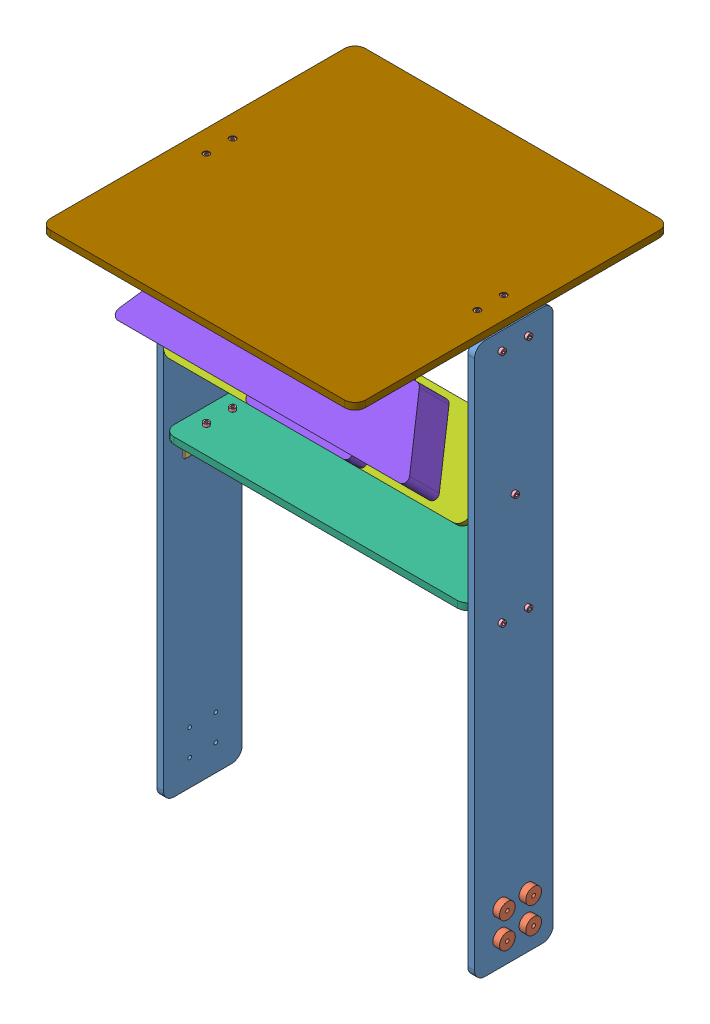
SolidWorks assembly Assembly_real_stairs_top_2, configuration Default. Lengths in mm.
Overall size (315.39 531.34 300).
62 component instances, 9 part files, 50 mates.
Components (placement in the parent):
- Part11-4: Part11 [Default] at (362.0256 34.666 386.9752) x (0 -1 0) z (0 0 1) size (525 6.35 75)
- Part11-5: Part11 [Default] at (72.0356 34.666 386.9752) x (0 -1 0) z (0 0 -1) size (525 6.35 75)
- washer-17: washer [Default] at (368.3756 -202.834 399.4752) x (0 0 -1) z (0 -1 0) size (15 6.35 15)
- washer-18: washer [Default] at (368.3756 -177.834 399.4752) x (0 0 -1) z (0 -1 0) size (15 6.35 15)
- washer-19: washer [Default] at (368.3756 -202.834 374.4752) x (0 0 -1) z (0 -1 0) size (15 6.35 15)
- washer-20: washer [Default] at (368.3756 -177.834 374.4752) x (0 0 -1) z (0 -1 0) size (15 6.35 15)
- washer-21: washer [Default] at (65.6856 -202.834 399.4752) x (0 0 1) z (0 -1 0) size (15 6.35 15)
- washer-22: washer [Default] at (65.6856 -177.834 399.4752) x (0 0 1) z (0 -1 0) size (15 6.35 15)
- washer-23: washer [Default] at (65.6856 -202.834 374.4752) x (0 0 1) z (0 -1 0) size (15 6.35 15)
- washer-24: washer [Default] at (65.6856 -177.834 374.4752) x (0 0 1) z (0 -1 0) size (15 6.35 15)
- 1556A410_BRACKET-17: 1556A410_BRACKET [1556A41] at (72.0356 73.041 399.4752) x (1 0 0) z (0 -1 0) size (25.4 12.7 25.4)
- 91290A123_BLACK-OXIDE CLASS 12.9 SOCKET HEAD CAP SCREW-23: 91290A123_BLACK-OXIDE CLASS 12.9 SOCKET HEAD CAP SCREW [91290A123] at (85.6856 57.166 399.4752) x (0 0 -1) z (1 0 0) size (5.5 5.5 23.27)
- 92497A200_ZINC YELLOW-CHROMATE PLATED STEEL HEX NUT-24: 92497A200_ZINC YELLOW-CHROMATE PLATED STEEL HEX NUT [92497A200] at (75.0136 57.166 399.4752) x (0 0 -1) z (1 0 0) size (5.5 6.35 2.78)
- 1556A410_BRACKET-18: 1556A410_BRACKET [1556A41] at (72.0356 73.041 374.4752) x (1 0 0) z (0 -1 0) size (25.4 12.7 25.4)
- 91290A123_BLACK-OXIDE CLASS 12.9 SOCKET HEAD CAP SCREW-24: 91290A123_BLACK-OXIDE CLASS 12.9 SOCKET HEAD CAP SCREW [91290A123] at (85.6856 57.166 374.4752) x (0 0 -1) z (1 0 0) size (5.5 5.5 23.27)
- 92497A200_ZINC YELLOW-CHROMATE PLATED STEEL HEX NUT-25: 92497A200_ZINC YELLOW-CHROMATE PLATED STEEL HEX NUT [92497A200] at (75.0136 57.166 374.4752) x (0 0 -1) z (1 0 0) size (5.5 6.35 2.78)
- 1556A410_BRACKET-19: 1556A410_BRACKET [1556A41] at (72.0356 297.161 399.4752) x (1 0 0) z (0 -1 0) size (25.4 12.7 25.4)
- 91290A123_BLACK-OXIDE CLASS 12.9 SOCKET HEAD CAP SCREW-25: 91290A123_BLACK-OXIDE CLASS 12.9 SOCKET HEAD CAP SCREW [91290A123] at (85.6856 281.286 399.4752) x (0 0 -1) z (1 0 0) size (5.5 5.5 23.27)
- 92497A200_ZINC YELLOW-CHROMATE PLATED STEEL HEX NUT-26: 92497A200_ZINC YELLOW-CHROMATE PLATED STEEL HEX NUT [92497A200] at (75.0136 281.286 399.4752) x (0 0 -1) z (1 0 0) size (5.5 6.35 2.78)
- 1556A410_BRACKET-20: 1556A410_BRACKET [1556A41] at (72.0356 297.161 374.4752) x (1 0 0) z (0 -1 0) size (25.4 12.7 25.4)
- 91290A123_BLACK-OXIDE CLASS 12.9 SOCKET HEAD CAP SCREW-26: 91290A123_BLACK-OXIDE CLASS 12.9 SOCKET HEAD CAP SCREW [91290A123] at (85.6856 281.286 374.4752) x (0 0 -1) z (1 0 0) size (5.5 5.5 23.27)
- 92497A200_ZINC YELLOW-CHROMATE PLATED STEEL HEX NUT-27: 92497A200_ZINC YELLOW-CHROMATE PLATED STEEL HEX NUT [92497A200] at (75.0136 281.286 374.4752) x (0 0 -1) z (1 0 0) size (5.5 6.35 2.78)
- 1556A410_BRACKET-21: 1556A410_BRACKET [1556A41] at (362.0256 73.041 399.4752) x (-1 0 0) z (0 -1 0) size (25.4 12.7 25.4)
- 91290A123_BLACK-OXIDE CLASS 12.9 SOCKET HEAD CAP SCREW-27: 91290A123_BLACK-OXIDE CLASS 12.9 SOCKET HEAD CAP SCREW [91290A123] at (348.3756 57.166 399.4752) x (0 0 1) z (-1 0 0) size (5.5 5.5 23.27)
- 92497A200_ZINC YELLOW-CHROMATE PLATED STEEL HEX NUT-28: 92497A200_ZINC YELLOW-CHROMATE PLATED STEEL HEX NUT [92497A200] at (359.0476 57.166 399.4752) x (0 0 -1) z (1 0 0) size (5.5 6.35 2.78)
- 1556A410_BRACKET-22: 1556A410_BRACKET [1556A41] at (362.0256 73.041 374.4752) x (-1 0 0) z (0 -1 0) size (25.4 12.7 25.4)
- 1556A410_BRACKET-23: 1556A410_BRACKET [1556A41] at (362.0256 297.161 399.4752) x (-1 0 0) z (0 -1 0) size (25.4 12.7 25.4)
- 1556A410_BRACKET-24: 1556A410_BRACKET [1556A41] at (362.0256 297.161 374.4752) x (-1 0 0) z (0 -1 0) size (25.4 12.7 25.4)
- 91290A123_BLACK-OXIDE CLASS 12.9 SOCKET HEAD CAP SCREW-28: 91290A123_BLACK-OXIDE CLASS 12.9 SOCKET HEAD CAP SCREW [91290A123] at (348.3756 57.166 374.4752) x (0 0 1) z (-1 0 0) size (5.5 5.5 23.27)
- 91290A123_BLACK-OXIDE CLASS 12.9 SOCKET HEAD CAP SCREW-29: 91290A123_BLACK-OXIDE CLASS 12.9 SOCKET HEAD CAP SCREW [91290A123] at (348.3756 281.286 399.4752) x (0 0 1) z (-1 0 0) size (5.5 5.5 23.27)
- 91290A123_BLACK-OXIDE CLASS 12.9 SOCKET HEAD CAP SCREW-30: 91290A123_BLACK-OXIDE CLASS 12.9 SOCKET HEAD CAP SCREW [91290A123] at (348.3756 281.286 374.4752) x (0 0 1) z (-1 0 0) size (5.5 5.5 23.27)
- 92497A200_ZINC YELLOW-CHROMATE PLATED STEEL HEX NUT-29: 92497A200_ZINC YELLOW-CHROMATE PLATED STEEL HEX NUT [92497A200] at (359.0476 57.166 374.4752) x (0 0 -1) z (1 0 0) size (5.5 6.35 2.78)
- 92497A200_ZINC YELLOW-CHROMATE PLATED STEEL HEX NUT-30: 92497A200_ZINC YELLOW-CHROMATE PLATED STEEL HEX NUT [92497A200] at (359.0476 281.286 399.4752) x (0 0 -1) z (1 0 0) size (5.5 6.35 2.78)
- 92497A200_ZINC YELLOW-CHROMATE PLATED STEEL HEX NUT-31: 92497A200_ZINC YELLOW-CHROMATE PLATED STEEL HEX NUT [92497A200] at (359.0476 281.286 374.4752) x (0 0 -1) z (1 0 0) size (5.5 6.35 2.78)
- Part5-2: Part5 [Default] at (217.0306 73.041 386.9752) size (290 6.35 75)
- 91290A123_BLACK-OXIDE CLASS 12.9 SOCKET HEAD CAP SCREW-31: 91290A123_BLACK-OXIDE CLASS 12.9 SOCKET HEAD CAP SCREW [91290A123] at (87.9106 59.391 399.4752) x (1 0 0) z (0 -1 0) size (5.5 5.5 23.27)
- 92497A200_ZINC YELLOW-CHROMATE PLATED STEEL HEX NUT-33: 92497A200_ZINC YELLOW-CHROMATE PLATED STEEL HEX NUT [92497A200] at (87.9106 70.063 399.4752) x (1 0 0) z (0 -1 0) size (5.5 6.35 2.78)
- 91290A123_BLACK-OXIDE CLASS 12.9 SOCKET HEAD CAP SCREW-32: 91290A123_BLACK-OXIDE CLASS 12.9 SOCKET HEAD CAP SCREW [91290A123] at (87.9106 59.391 374.4752) x (1 0 0) z (0 -1 0) size (5.5 5.5 23.27)
- 92497A200_ZINC YELLOW-CHROMATE PLATED STEEL HEX NUT-34: 92497A200_ZINC YELLOW-CHROMATE PLATED STEEL HEX NUT [92497A200] at (87.9106 70.063 374.4752) x (1 0 0) z (0 -1 0) size (5.5 6.35 2.78)
- 91290A123_BLACK-OXIDE CLASS 12.9 SOCKET HEAD CAP SCREW-38: 91290A123_BLACK-OXIDE CLASS 12.9 SOCKET HEAD CAP SCREW [91290A123] at (346.1506 59.391 399.4752) x (1 0 0) z (0 -1 0) size (5.5 5.5 23.27)
- 92497A200_ZINC YELLOW-CHROMATE PLATED STEEL HEX NUT-40: 92497A200_ZINC YELLOW-CHROMATE PLATED STEEL HEX NUT [92497A200] at (346.1506 70.063 399.4752) x (1 0 0) z (0 -1 0) size (5.5 6.35 2.78)
- 1556A410_BRACKET-25: 1556A410_BRACKET [1556A41] at (72.0356 168.3913 398.2005) x (1 0 0) z (0 -0.707107 -0.707107) size (25.4 12.7 25.4)
- 1556A410_BRACKET-26: 1556A410_BRACKET [1556A41] at (362.0256 168.3913 398.2005) x (-1 0 0) z (0 -0.707107 -0.707107) size (25.4 12.7 25.4)
- Part2-2: Part2 [Default] at (217.0306 168.3913 398.2005) x (1 0 0) z (0 -0.707107 0.707107) size (290 6.35 75)
- 91290A123_BLACK-OXIDE CLASS 12.9 SOCKET HEAD CAP SCREW-43: 91290A123_BLACK-OXIDE CLASS 12.9 SOCKET HEAD CAP SCREW [91290A123] at (87.9106 158.7393 388.5485) x (0 0.707107 -0.707107) z (0 -0.707107 -0.707107) size (5.5 5.5 23.27)
- 92497A200_ZINC YELLOW-CHROMATE PLATED STEEL HEX NUT-45: 92497A200_ZINC YELLOW-CHROMATE PLATED STEEL HEX NUT [92497A200] at (87.9106 166.2856 396.0948) x (1 0 0) z (0 -0.707107 -0.707107) size (5.5 6.35 2.78)
- 91290A123_BLACK-OXIDE CLASS 12.9 SOCKET HEAD CAP SCREW-44: 91290A123_BLACK-OXIDE CLASS 12.9 SOCKET HEAD CAP SCREW [91290A123] at (346.1506 158.7393 388.5485) x (0 0.707107 -0.707107) z (0 -0.707107 -0.707107) size (5.5 5.5 23.27)
- 92497A200_ZINC YELLOW-CHROMATE PLATED STEEL HEX NUT-46: 92497A200_ZINC YELLOW-CHROMATE PLATED STEEL HEX NUT [92497A200] at (346.1506 166.2856 396.0948) x (1 0 0) z (0 -0.707107 -0.707107) size (5.5 6.35 2.78)
- 91290A123_BLACK-OXIDE CLASS 12.9 SOCKET HEAD CAP SCREW-45: 91290A123_BLACK-OXIDE CLASS 12.9 SOCKET HEAD CAP SCREW [91290A123] at (85.6856 157.166 386.9752) x (0 0 -1) z (1 0 0) size (5.5 5.5 23.27)
- 92497A200_ZINC YELLOW-CHROMATE PLATED STEEL HEX NUT-47: 92497A200_ZINC YELLOW-CHROMATE PLATED STEEL HEX NUT [92497A200] at (75.0136 157.166 386.9752) x (0 1 0) z (-1 0 0) size (5.5 6.35 2.78)
- 91290A123_BLACK-OXIDE CLASS 12.9 SOCKET HEAD CAP SCREW-46: 91290A123_BLACK-OXIDE CLASS 12.9 SOCKET HEAD CAP SCREW [91290A123] at (348.3756 157.166 386.9752) x (0 0 -1) z (-1 0 0) size (5.5 5.5 23.27)
- 92497A200_ZINC YELLOW-CHROMATE PLATED STEEL HEX NUT-48: 92497A200_ZINC YELLOW-CHROMATE PLATED STEEL HEX NUT [92497A200] at (359.0476 157.166 386.9752) x (0 -0.924225 -0.381849) z (-1 0 0) size (5.5 6.35 2.78)
- kinect-1: kinect [Default] at (217.0306 231.742 393.3276) x (1 0 0) z (0 -0.707107 0.707107) size (278.26 75 75)
- Part61-1: Part61 [Default] at (217.0306 297.161 386.9752) size (300 6.35 300)
- 91290A123_BLACK-OXIDE CLASS 12.9 SOCKET HEAD CAP SCREW-47: 91290A123_BLACK-OXIDE CLASS 12.9 SOCKET HEAD CAP SCREW [91290A123] at (87.9106 280.011 399.4752) x (1 0 0) z (0 -1 0) size (5.5 5.5 23.27)
- 92497A200_ZINC YELLOW-CHROMATE PLATED STEEL HEX NUT-49: 92497A200_ZINC YELLOW-CHROMATE PLATED STEEL HEX NUT [92497A200] at (87.9106 294.183 399.4752) x (1 0 0) z (0 -1 0) size (5.5 6.35 2.78)
- 91290A123_BLACK-OXIDE CLASS 12.9 SOCKET HEAD CAP SCREW-48: 91290A123_BLACK-OXIDE CLASS 12.9 SOCKET HEAD CAP SCREW [91290A123] at (346.1506 280.011 399.4752) x (1 0 0) z (0 -1 0) size (5.5 5.5 23.27)
- 91290A123_BLACK-OXIDE CLASS 12.9 SOCKET HEAD CAP SCREW-49: 91290A123_BLACK-OXIDE CLASS 12.9 SOCKET HEAD CAP SCREW [91290A123] at (87.9106 280.011 374.4752) x (1 0 0) z (0 -1 0) size (5.5 5.5 23.27)
- 91290A123_BLACK-OXIDE CLASS 12.9 SOCKET HEAD CAP SCREW-50: 91290A123_BLACK-OXIDE CLASS 12.9 SOCKET HEAD CAP SCREW [91290A123] at (346.1506 280.011 374.4752) x (1 0 0) z (0 -1 0) size (5.5 5.5 23.27)
- 92497A200_ZINC YELLOW-CHROMATE PLATED STEEL HEX NUT-50: 92497A200_ZINC YELLOW-CHROMATE PLATED STEEL HEX NUT [92497A200] at (346.1506 294.183 399.4752) x (1 0 0) z (0 -1 0) size (5.5 6.35 2.78)
- 92497A200_ZINC YELLOW-CHROMATE PLATED STEEL HEX NUT-51: 92497A200_ZINC YELLOW-CHROMATE PLATED STEEL HEX NUT [92497A200] at (87.9106 294.183 374.4752) x (1 0 0) z (0 -1 0) size (5.5 6.35 2.78)
- 92497A200_ZINC YELLOW-CHROMATE PLATED STEEL HEX NUT-52: 92497A200_ZINC YELLOW-CHROMATE PLATED STEEL HEX NUT [92497A200] at (346.1506 294.183 374.4752) x (1 0 0) z (0 -1 0) size (5.5 6.35 2.78)
Mates (geometry in assembly coordinates):
- Coincident5: coincident anti-aligned: circle of Part11-4; circle of washer-17
- Coincident6: coincident anti-aligned: circle of Part11-5; circle of washer-21
- Concentric8: concentric anti-aligned: circle of Part11-5; circle of 1556A410_BRACKET-17
- Coincident7: coincident aligned: circle of Part11-5; plane of 1556A410_BRACKET-17 through (72.0356 47.641 405.8252) normal (-1 0 0)
- Coincident8: coincident anti-aligned: plane of Part11-5 through (65.6856 34.666 386.9752) normal (-1 0 0); plane of 91290A123_BLACK-OXIDE CLASS 12.9 SOCKET HEAD CAP SCREW-23 through (65.6856 57.166 399.4752) normal (1 0 0)
- Concentric9: concentric anti-aligned: circle of Part11-5; circle of 91290A123_BLACK-OXIDE CLASS 12.9 SOCKET HEAD CAP SCREW-23
- Concentric10: concentric anti-aligned: circle of 1556A410_BRACKET-17; circle of 92497A200_ZINC YELLOW-CHROMATE PLATED STEEL HEX NUT-24
- Coincident11: coincident anti-aligned: plane of 1556A410_BRACKET-17 through (73.8136 47.641 405.8252) normal (1 0 0); plane of 92497A200_ZINC YELLOW-CHROMATE PLATED STEEL HEX NUT-24 through (73.8136 58.7537 402.2252) normal (-1 0 0)
- Coincident12: coincident aligned: circle of Part11-4; plane of 1556A410_BRACKET-21 through (362.0256 47.641 393.1252) normal (1 0 0)
- Concentric11: concentric anti-aligned: circle of Part11-4; circle of 1556A410_BRACKET-21
- Coincident13: coincident anti-aligned: circle of Part11-4; plane of 91290A123_BLACK-OXIDE CLASS 12.9 SOCKET HEAD CAP SCREW-27 through (368.3756 57.166 399.4752) normal (-1 0 0)
- Concentric12: concentric anti-aligned: circle of Part11-4; circle of 91290A123_BLACK-OXIDE CLASS 12.9 SOCKET HEAD CAP SCREW-27
- Concentric13: concentric aligned: circle of 1556A410_BRACKET-21; circle of 92497A200_ZINC YELLOW-CHROMATE PLATED STEEL HEX NUT-28
- Coincident14: coincident anti-aligned: circle of 1556A410_BRACKET-21; plane of 92497A200_ZINC YELLOW-CHROMATE PLATED STEEL HEX NUT-28 through (360.2476 58.7537 402.2252) normal (1 0 0)
- Concentric14: concentric anti-aligned: circle of 1556A410_BRACKET-19; circle of Part5-2
- Coincident16: coincident anti-aligned: plane of 1556A410_BRACKET-17 through (74.7026 73.041 405.8252) normal (0 1 0); plane of Part5-2 through (217.0306 73.041 386.9752) normal (0 -1 0)
- Coincident17: coincident anti-aligned: circle of Part5-2; plane of 91290A123_BLACK-OXIDE CLASS 12.9 SOCKET HEAD CAP SCREW-31 through (87.9106 79.391 399.4752) normal (0 -1 0)
- Concentric15: concentric anti-aligned: circle of Part5-2; circle of 91290A123_BLACK-OXIDE CLASS 12.9 SOCKET HEAD CAP SCREW-31
- Concentric18: concentric aligned: circle of 1556A410_BRACKET-17; circle of 92497A200_ZINC YELLOW-CHROMATE PLATED STEEL HEX NUT-33
- Coincident22: coincident anti-aligned: plane of 1556A410_BRACKET-17 through (74.7026 71.263 405.8252) normal (0 -1 0); plane of 92497A200_ZINC YELLOW-CHROMATE PLATED STEEL HEX NUT-33 through (85.1606 71.263 401.0629) normal (0 1 0)
- Concentric19: concentric aligned: circle of Part11-5; circle of 1556A410_BRACKET-25
- Coincident23: coincident anti-aligned: circle of Part11-5; plane of 1556A410_BRACKET-25 through (72.0356 145.9407 384.7301) normal (-1 0 0)
- Concentric20: concentric aligned: circle of Part11-4; circle of 1556A410_BRACKET-26
- Coincident24: coincident anti-aligned: circle of Part11-4; plane of 1556A410_BRACKET-26 through (362.0256 154.921 375.7499) normal (1 0 0)
- Coincident25: coincident anti-aligned: plane of 1556A410_BRACKET-25 through (74.7026 163.9012 402.6907) normal (0 0.707107 0.707107); plane of Part2-2 through (217.0306 168.3913 398.2005) normal (0 -0.707107 -0.707107)
- Concentric21: concentric anti-aligned: circle of 1556A410_BRACKET-26; circle of Part2-2
- Coincident26: coincident anti-aligned: plane of Part2-2 through (217.0306 172.8815 402.6907) normal (0 0.707107 0.707107); plane of 91290A123_BLACK-OXIDE CLASS 12.9 SOCKET HEAD CAP SCREW-43 through (87.9106 172.8815 402.6907) normal (0 -0.707107 -0.707107)
- Concentric22: concentric anti-aligned: circle of Part2-2; circle of 91290A123_BLACK-OXIDE CLASS 12.9 SOCKET HEAD CAP SCREW-43
- Coincident27: coincident anti-aligned: plane of 1556A410_BRACKET-25 through (74.7026 162.644 401.4334) normal (0 -0.707107 -0.707107); plane of 92497A200_ZINC YELLOW-CHROMATE PLATED STEEL HEX NUT-45 through (85.1606 166.0114 398.066) normal (0 0.707107 0.707107)
- Concentric23: concentric anti-aligned: circle of 1556A410_BRACKET-25; circle of 92497A200_ZINC YELLOW-CHROMATE PLATED STEEL HEX NUT-45
- Coincident28: coincident anti-aligned: plane of Part11-5 through (65.6856 34.666 386.9752) normal (-1 0 0); plane of 91290A123_BLACK-OXIDE CLASS 12.9 SOCKET HEAD CAP SCREW-45 through (65.6856 157.166 386.9752) normal (1 0 0)
- Concentric24: concentric aligned: circle of Part11-5; circle of 91290A123_BLACK-OXIDE CLASS 12.9 SOCKET HEAD CAP SCREW-45
- Coincident29: coincident anti-aligned: plane of 1556A410_BRACKET-25 through (73.8136 145.9407 384.7301) normal (1 0 0); plane of 92497A200_ZINC YELLOW-CHROMATE PLATED STEEL HEX NUT-47 through (73.8136 154.416 385.3875) normal (-1 0 0)
- Concentric25: concentric anti-aligned: circle of 1556A410_BRACKET-25; circle of 92497A200_ZINC YELLOW-CHROMATE PLATED STEEL HEX NUT-47
- Coincident30: coincident anti-aligned: plane of Part11-4 through (368.3756 34.666 386.9752) normal (1 0 0); plane of 91290A123_BLACK-OXIDE CLASS 12.9 SOCKET HEAD CAP SCREW-46 through (368.3756 157.166 386.9752) normal (-1 0 0)
- Concentric26: concentric aligned: circle of Part11-4; circle of 91290A123_BLACK-OXIDE CLASS 12.9 SOCKET HEAD CAP SCREW-46
- Coincident31: coincident anti-aligned: plane of 1556A410_BRACKET-26 through (360.2476 154.921 375.7499) normal (-1 0 0); plane of 92497A200_ZINC YELLOW-CHROMATE PLATED STEEL HEX NUT-48 through (360.2476 159.1014 389.4927) normal (1 0 0)
- Concentric27: concentric anti-aligned: circle of 1556A410_BRACKET-26; circle of 92497A200_ZINC YELLOW-CHROMATE PLATED STEEL HEX NUT-48
- Concentric28: concentric anti-aligned: circle of 1556A410_BRACKET-23; circle of Part61-1
- Coincident32: coincident anti-aligned: plane of 1556A410_BRACKET-23 through (359.3586 297.161 393.1252) normal (0 1 0); plane of Part61-1 through (217.0306 297.161 386.9752) normal (0 -1 0)
- Coincident33: coincident anti-aligned: plane of Part2-2 through (217.0306 172.8815 402.6907) normal (0 0.707107 0.707107); plane of kinect-1 through (217.0306 206.9933 368.5789) normal (0 -0.707107 -0.707107)
- Coincident36: coincident anti-aligned: plane of Part2-2 through (217.0306 172.8815 402.6907) normal (0 0.707107 0.707107); plane of kinect-1 through (217.0306 206.9933 368.5789) normal (0 -0.707107 -0.707107)
- Coincident37: coincident anti-aligned: line of Part2-2 through (82.0306 146.365 429.2072) axis (1 0 0); line of kinect-1 through (262.0306 146.365 429.2072) axis (-1 0 0)
- Distance2: distance = 95 mm: line of kinect-1 through (167.0306 149.9005 425.6716) axis (0 0.707107 -0.707107); line of Part2-2 through (72.0306 192.3269 383.2452) axis (0 -0.707107 0.707107)
- Concentric29: concentric anti-aligned: circle of 1556A410_BRACKET-19; circle of Part61-1
- Coincident38: coincident anti-aligned: plane of 1556A410_BRACKET-19 through (74.7026 297.161 405.8252) normal (0 1 0); plane of Part61-1 through (217.0306 297.161 386.9752) normal (0 -1 0)
- Coincident39: coincident anti-aligned: plane of Part61-1 through (87.9106 300.011 399.4752) normal (0 1 0); plane of 91290A123_BLACK-OXIDE CLASS 12.9 SOCKET HEAD CAP SCREW-47 through (87.9106 300.011 399.4752) normal (0 -1 0)
- Concentric30: concentric aligned: circle of Part61-1; circle of 91290A123_BLACK-OXIDE CLASS 12.9 SOCKET HEAD CAP SCREW-47
- Coincident40: coincident anti-aligned: plane of 1556A410_BRACKET-19 through (74.7026 295.383 405.8252) normal (0 -1 0); plane of 92497A200_ZINC YELLOW-CHROMATE PLATED STEEL HEX NUT-49 through (85.1606 295.383 401.0629) normal (0 1 0)
- Concentric31: concentric anti-aligned: circle of 1556A410_BRACKET-19; circle of 92497A200_ZINC YELLOW-CHROMATE PLATED STEEL HEX NUT-49
